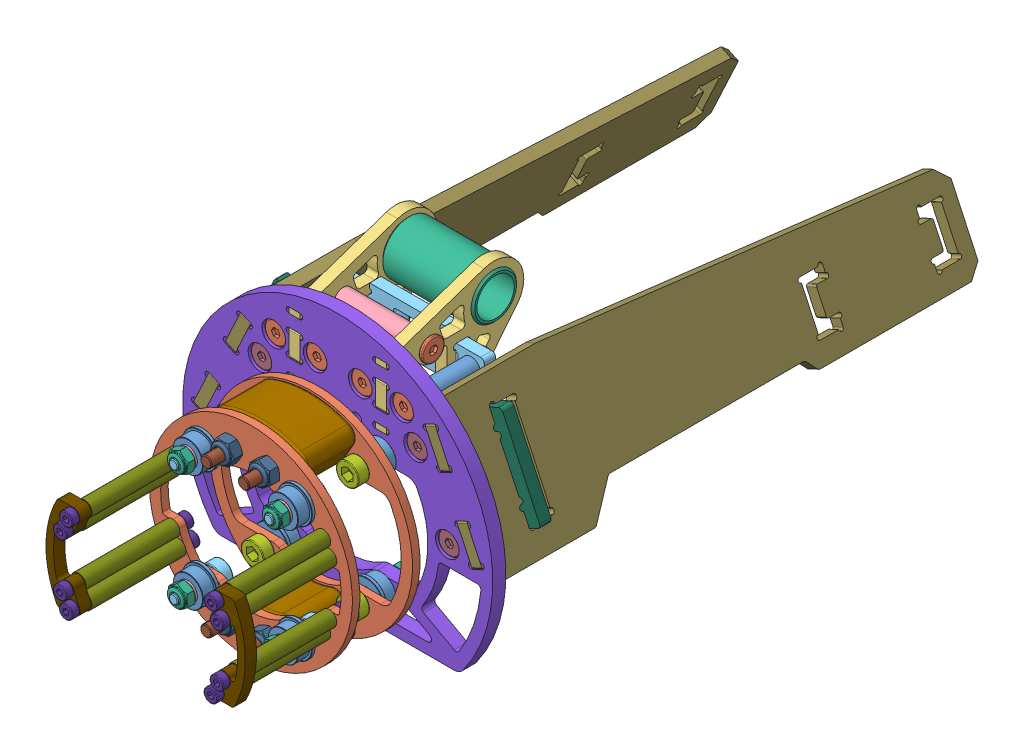
SolidWorks assembly 弹轮前轴系, configuration 默认. Lengths in mm.
Overall size (82.5 72.5 186.6).
121 component instances, 24 part files, 98 mates.
Components (placement in the parent):
- 法兰轴承3×8×4-1: 法兰轴承3×8×4 [默认] at (-12.6392 15.5 11.1) x (-0.660582 -0.750754 0) z (0 0 1) size (9.2 9.2 4)
- 弹轮前轴承板1_2mm-1: 弹轮前轴承板1_2mm [弹轮前轴承板1（限位）_2mm] at (0 0 8) size (54 54 2)
- 3×5×0.1 平垫-1: 3×5×0.1 平垫 [默认] at (-12.6392 15.5 9.05) size (5 5 0.1)
- 3×5×0.5 平垫-1: 3×5×0.5 平垫 [默认] at (-12.6392 15.5 13.35) size (5 5 0.5)
- 3×5×0.5 平垫-2: 3×5×0.5 平垫 [默认] at (12.6392 15.5 13.35) x (-1 0 0) z (0 0 -1) size (5 5 0.5)
- 法兰轴承3×8×4-2: 法兰轴承3×8×4 [默认] at (12.6392 15.5 11.1) x (-0.660582 0.750754 0) z (0 0 1) size (9.2 9.2 4)
- 3×5×0.1 平垫-2: 3×5×0.1 平垫 [默认] at (12.6392 15.5 9.05) x (-1 0 0) z (0 0 -1) size (5 5 0.1)
- 3×6×M2.5塞打螺丝-1: 3×6×M2.5塞打螺丝 [默认] at (-12.6392 15.5 10.5) x (0 0 1) z (-0.999028 0.044087 0) size (13 6 6)
- 3×6×M2.5塞打螺丝-2: 3×6×M2.5塞打螺丝 [默认] at (12.6392 15.5 10.5) x (0 0 1) z (-0.999028 -0.044087 0) size (13 6 6)
- M2.5防松-1: M2.5防松 [默认] at (-12.6392 15.5 14.75) x (-0.917308 -0.398178 0) z (-0.398178 0.917308 0) size (5.77 2.99 5)
- M2.5防松-2: M2.5防松 [默认] at (12.6392 15.5 14.75) x (0.917308 -0.398178 0) z (-0.398178 -0.917308 0) size (5.77 2.99 5)
- 3×5×0.5 平垫-3: 3×5×0.5 平垫 [默认] at (-12.6392 -15.5 13.35) x (1 0 0) z (0 0 -1) size (5 5 0.5)
- 法兰轴承3×8×4-3: 法兰轴承3×8×4 [默认] at (-12.6392 -15.5 11.1) x (0.660582 -0.750754 0) z (0 0 1) size (9.2 9.2 4)
- 3×5×0.1 平垫-3: 3×5×0.1 平垫 [默认] at (-12.6392 -15.5 9.05) x (1 0 0) z (0 0 -1) size (5 5 0.1)
- 3×6×M2.5塞打螺丝-3: 3×6×M2.5塞打螺丝 [默认] at (-12.6392 -15.5 10.5) x (0 0 1) z (0.999028 0.044087 0) size (13 6 6)
- M2.5防松-3: M2.5防松 [默认] at (-12.6392 -15.5 14.75) x (-0.917308 0.398178 0) z (0.398178 0.917308 0) size (5.77 2.99 5)
- 3×5×0.5 平垫-4: 3×5×0.5 平垫 [默认] at (12.6392 -15.5 13.35) x (-1 0 0) z (0 0 1) size (5 5 0.5)
- 法兰轴承3×8×4-4: 法兰轴承3×8×4 [默认] at (12.6392 -15.5 11.1) x (0.660582 0.750754 0) z (0 0 1) size (9.2 9.2 4)
- 3×5×0.1 平垫-4: 3×5×0.1 平垫 [默认] at (12.6392 -15.5 9.05) x (-1 0 0) z (0 0 1) size (5 5 0.1)
- 3×6×M2.5塞打螺丝-4: 3×6×M2.5塞打螺丝 [默认] at (12.6392 -15.5 10.5) x (0 0 1) z (0.999028 -0.044087 0) size (13 6 6)
- M2.5防松-4: M2.5防松 [默认] at (12.6392 -15.5 14.75) x (0.917308 0.398178 0) z (0.398178 -0.917308 0) size (5.77 2.99 5)
- 弹轮前轴承板1_2mm-3: 弹轮前轴承板1_2mm [默认] at (0 0 -8) size (54 54 2)
- 3×5×0.1 平垫-5: 3×5×0.1 平垫 [默认] at (12.6392 -15.5 -9.05) x (-1 0 0) z (0 0 1) size (5 5 0.1)
- 法兰轴承3×8×4-5: 法兰轴承3×8×4 [默认] at (12.6392 -15.5 -11.1) x (-0.660582 -0.750754 0) z (0 0 -1) size (9.2 9.2 4)
- 3×5×0.1 平垫-6: 3×5×0.1 平垫 [默认] at (-12.6392 -15.5 -9.05) x (1 0 0) z (0 0 -1) size (5 5 0.1)
- 法兰轴承3×8×4-6: 法兰轴承3×8×4 [默认] at (-12.6392 -15.5 -11.1) x (-0.660582 0.750754 0) z (0 0 -1) size (9.2 9.2 4)
- 3×5×0.1 平垫-7: 3×5×0.1 平垫 [默认] at (-12.6392 15.5 -9.05) size (5 5 0.1)
- 法兰轴承3×8×4-7: 法兰轴承3×8×4 [默认] at (-12.6392 15.5 -11.1) x (0.660582 0.750754 0) z (0 0 -1) size (9.2 9.2 4)
- 3×5×0.1 平垫-8: 3×5×0.1 平垫 [默认] at (12.6392 15.5 -9.05) x (-1 0 0) z (0 0 -1) size (5 5 0.1)
- 法兰轴承3×8×4-8: 法兰轴承3×8×4 [默认] at (12.6392 15.5 -11.1) x (0.660582 -0.750754 0) z (0 0 -1) size (9.2 9.2 4)
- 3×10×M2.5塞打螺丝-1: 3×10×M2.5塞打螺丝 [默认] at (-12.6392 -15.5 -12.5) x (0 0 -1) z (0.867305 -0.497776 0) size (17 6 6)
- 3×10×M2.5塞打螺丝-2: 3×10×M2.5塞打螺丝 [默认] at (12.6392 -15.5 -12.5) x (0 0 -1) z (0.867305 0.497776 0) size (17 6 6)
- 3×10×M2.5塞打螺丝-3: 3×10×M2.5塞打螺丝 [默认] at (-12.6392 15.5 -12.5) x (0 0 -1) z (-0.867305 -0.497776 0) size (17 6 6)
- 3×10×M2.5塞打螺丝-4: 3×10×M2.5塞打螺丝 [默认] at (12.6392 15.5 -12.5) x (0 0 -1) z (-0.867305 0.497776 0) size (17 6 6)
- 3×5×0.5 平垫-5: 3×5×0.5 平垫 [默认] at (-12.6392 15.5 -13.35) size (5 5 0.5)
- 3×5×0.5 平垫-6: 3×5×0.5 平垫 [默认] at (12.6392 15.5 -13.35) x (-1 0 0) z (0 0 -1) size (5 5 0.5)
- 3×5×0.5 平垫-7: 3×5×0.5 平垫 [默认] at (-12.6392 -15.5 -13.35) x (1 0 0) z (0 0 -1) size (5 5 0.5)
- 3×5×0.5 平垫-8: 3×5×0.5 平垫 [默认] at (12.6392 -15.5 -13.35) x (-1 0 0) z (0 0 1) size (5 5 0.5)
- 弹轮前轴承板2_3.5mm-1: 弹轮前轴承板2_3.5mm [默认] at (0 0 -15.85) x (-1 0 0) z (0 0 1) size (82.5 66.75 3.5)
- M2.5防松-5: M2.5防松 [默认] at (-12.6392 15.5 -18.75) x (1 0 0) z (0 1 0) size (5.77 2.99 5)
- M2.5防松-6: M2.5防松 [默认] at (12.6392 15.5 -18.75) x (-1 0 0) z (0 -1 0) size (5.77 2.99 5)
- M2.5防松-7: M2.5防松 [默认] at (-12.6392 -15.5 -18.75) x (1 0 0) z (0 1 0) size (5.77 2.99 5)
- M2.5防松-8: M2.5防松 [默认] at (12.6392 -15.5 -18.75) x (-1 0 0) z (0 -1 0) size (5.77 2.99 5)
- 3×5×0.5 平垫-9: 3×5×0.5 平垫 [默认] at (-12.6392 15.5 -13.85) size (5 5 0.5)
- 3×5×0.5 平垫-10: 3×5×0.5 平垫 [默认] at (12.6392 15.5 -13.85) x (-1 0 0) z (0 0 -1) size (5 5 0.5)
- 3×5×0.5 平垫-11: 3×5×0.5 平垫 [默认] at (-12.6392 -15.5 -13.85) x (1 0 0) z (0 0 -1) size (5 5 0.5)
- 3×5×0.5 平垫-12: 3×5×0.5 平垫 [默认] at (12.6392 -15.5 -13.85) x (-1 0 0) z (0 0 1) size (5 5 0.5)
- 弹轮前轴系垫块-1: 弹轮前轴系垫块 [默认] at origin size (24.62 12.25 14.46)
- 弹轮前轴系垫块-2: 弹轮前轴系垫块 [默认] x (1 0 0) z (0 0 -1) size (24.62 12.25 14.46)
- M3防松-1: M3防松 [默认] at (-5 -19.5 10.4) x (1 0 0) z (0 -1 0) size (6.24 3.5 5.4)
- M3防松-2: M3防松 [默认] at (5 -19.5 10.4) x (-0.923728 -0.383049 0) z (-0.383049 0.923728 0) size (6.24 3.5 5.4)
- M3防松-3: M3防松 [默认] at (5 19.5 10.4) x (-0.923728 0.383049 0) z (0.383049 0.923728 0) size (6.24 3.5 5.4)
- M3防松-4: M3防松 [默认] at (-5 19.5 10.4) x (1 0 0) z (0 -1 0) size (6.24 3.5 5.4)
- M3×25扁头螺丝-1: M3×25扁头螺丝 [默认] at (5 -19.5 -9.5) x (-0.697349 0.716732 0) z (0 0 -1) size (6 6 26)
- M3×25扁头螺丝-2: M3×25扁头螺丝 [默认] at (-5 -19.5 -9.5) x (-0.570437 0.821341 0) z (0 0 -1) size (6 6 26)
- M3×25扁头螺丝-3: M3×25扁头螺丝 [默认] at (5 19.5 -9.5) x (0.697349 0.716732 0) z (0 0 -1) size (6 6 26)
- M3×25扁头螺丝-4: M3×25扁头螺丝 [默认] at (-5 19.5 -9.5) x (0.570437 0.821341 0) z (0 0 -1) size (6 6 26)
- 弹轮-轨道连接板1_3mm-1: 弹轮-轨道连接板1_3mm [默认] at (-30.8145 14.369 -82.6) x (0 0 1) z (-0.906308 0.422618 0) size (133.5 38 3)
- M3×6扁头螺丝-1: M3×6扁头螺丝 [默认] at (-20.6973 20.6851 -15.1) size (6 6 7)
- M3×6扁头螺丝-2: M3×6扁头螺丝 [默认] at (-29.1496 2.5589 -15.1) x (0.985984 -0.166838 0) z (0 0 1) size (6 6 7)
- M3×Φ5×10-1: M3×Φ5×10 [默认] at (-29.1496 2.5589 -22.6) size (5 5 10)
- M3×Φ5×10-2: M3×Φ5×10 [默认] at (-20.6973 20.6851 -22.6) size (5 5 10)
- 弹轮前轴承板3_3mm-1: 弹轮前轴承板3_3mm [默认] at (-24.9235 11.622 -29.1) x (0.906308 -0.422618 0) z (0 0 1) size (14.97 27 3)
- M3×6扁头螺丝-3: M3×6扁头螺丝 [默认] at (-20.6973 20.6851 -31.1) x (0.679475 0.733699 0) z (0 0 -1) size (6 6 7)
- M3×6扁头螺丝-4: M3×6扁头螺丝 [默认] at (-29.1496 2.5589 -31.1) x (0.733685 0.67949 0) z (0 0 -1) size (6 6 7)
- M3×6扁头螺丝-5: M3×6扁头螺丝 [默认] at (29.1496 2.5589 -31.1) x (0.733685 -0.67949 0) z (0 0 -1) size (6 6 7)
- M3×Φ5×10-3: M3×Φ5×10 [默认] at (29.1496 2.5589 -22.6) x (-1 0 0) z (0 0 -1) size (5 5 10)
- 弹轮前轴承板3_3mm-2: 弹轮前轴承板3_3mm [默认] at (24.9235 11.622 -29.1) x (-0.906308 -0.422618 0) z (0 0 -1) size (14.97 27 3)
- M3×Φ5×10-4: M3×Φ5×10 [默认] at (20.6973 20.6851 -22.6) x (-1 0 0) z (0 0 -1) size (5 5 10)
- M3×6扁头螺丝-6: M3×6扁头螺丝 [默认] at (20.6973 20.6851 -31.1) x (0.679475 -0.733699 0) z (0 0 -1) size (6 6 7)
- 弹轮-轨道连接板1_3mm-2: 弹轮-轨道连接板1_3mm [默认] at (30.8145 14.369 -82.6) x (0 0 1) z (-0.906308 -0.422618 0) size (133.5 38 3)
- M3×6扁头螺丝-7: M3×6扁头螺丝 [默认] at (29.1496 2.5589 -15.1) x (0.985984 0.166838 0) z (0 0 1) size (6 6 7)
- M3×6扁头螺丝-8: M3×6扁头螺丝 [默认] at (20.6973 20.6851 -15.1) size (6 6 7)
- M2×Φ4×25铝柱-1: M2×Φ4×25铝柱 [默认] at (-20.8567 -7 21.5) x (-0.830926 -0.556383 0) z (0 0 1) size (4 4 25)
- M2×Φ4×25铝柱-2: M2×Φ4×25铝柱 [默认] at (-19.2445 -10.6607 21.5) x (0.982865 0.184326 0) z (0 0 1) size (4 4 25)
- M2×8圆柱头螺丝-1: M2×8圆柱头螺丝 [默认] at (-19.2445 -10.6607 10) x (0 0 1) z (-0.980095 -0.198528 0) size (10 3.6 3.6)
- M2×8圆柱头螺丝-2: M2×8圆柱头螺丝 [默认] at (-20.8567 -7 10) x (0 0 1) z (-1 0 0) size (10 3.6 3.6)
- M2×8圆柱头螺丝-3: M2×8圆柱头螺丝 [默认] at (-19.2445 -10.6607 34) x (0 0 -1) z (0.941359 0.337405 0) size (10 3.6 3.6)
- M2×8圆柱头螺丝-4: M2×8圆柱头螺丝 [默认] at (-20.8567 -7 34) x (0 0 -1) z (0.953351 0.301864 0) size (10 3.6 3.6)
- M2×Φ4×25铝柱-3: M2×Φ4×25铝柱 [默认] at (20.8567 -7 21.5) x (0.830926 -0.556383 0) z (0 0 -1) size (4 4 25)
- M2×Φ4×25铝柱-4: M2×Φ4×25铝柱 [默认] at (19.2445 -10.6607 21.5) x (-0.982865 0.184326 0) z (0 0 -1) size (4 4 25)
- M2×8圆柱头螺丝-5: M2×8圆柱头螺丝 [默认] at (19.2445 -10.6607 34) x (0 0 -1) z (0.941359 -0.337405 0) size (10 3.6 3.6)
- M2×8圆柱头螺丝-6: M2×8圆柱头螺丝 [默认] at (20.8567 -7 34) x (0 0 -1) z (0.953351 -0.301864 0) size (10 3.6 3.6)
- M2×8圆柱头螺丝-7: M2×8圆柱头螺丝 [默认] at (19.2445 -10.6607 10) x (0 0 1) z (-0.980095 0.198528 0) size (10 3.6 3.6)
- M2×8圆柱头螺丝-8: M2×8圆柱头螺丝 [默认] at (20.8567 -7 10) x (0 0 1) z (-1 0 0) size (10 3.6 3.6)
- M2×8圆柱头螺丝-9: M2×8圆柱头螺丝 [默认] at (-20.8567 7 34) x (0 0 -1) z (-0.953351 0.301864 0) size (10 3.6 3.6)
- M2×8圆柱头螺丝-10: M2×8圆柱头螺丝 [默认] at (-19.2445 10.6607 34) x (0 0 -1) z (-0.941359 0.337405 0) size (10 3.6 3.6)
- M2×Φ4×25铝柱-5: M2×Φ4×25铝柱 [默认] at (-20.8567 7 21.5) x (-0.830926 0.556383 0) z (0 0 -1) size (4 4 25)
- M2×Φ4×25铝柱-6: M2×Φ4×25铝柱 [默认] at (-19.2445 10.6607 21.5) x (0.982865 -0.184326 0) z (0 0 -1) size (4 4 25)
- M2×8圆柱头螺丝-11: M2×8圆柱头螺丝 [默认] at (-19.2445 10.6607 10) x (0 0 1) z (0.980095 -0.198528 0) size (10 3.6 3.6)
- M2×8圆柱头螺丝-12: M2×8圆柱头螺丝 [默认] at (-20.8567 7 10) x (0 0 1) z (1 0 0) size (10 3.6 3.6)
- M2×8圆柱头螺丝-13: M2×8圆柱头螺丝 [默认] at (19.2445 10.6607 34) x (0 0 -1) z (-0.941359 -0.337405 0) size (10 3.6 3.6)
- M2×8圆柱头螺丝-14: M2×8圆柱头螺丝 [默认] at (20.8567 7 34) x (0 0 -1) z (-0.953351 -0.301864 0) size (10 3.6 3.6)
- M2×Φ4×25铝柱-7: M2×Φ4×25铝柱 [默认] at (19.2445 10.6607 21.5) x (-0.982865 -0.184326 0) z (0 0 1) size (4 4 25)
- M2×Φ4×25铝柱-8: M2×Φ4×25铝柱 [默认] at (20.8567 7 21.5) x (0.830926 0.556383 0) z (0 0 1) size (4 4 25)
- M2×8圆柱头螺丝-15: M2×8圆柱头螺丝 [默认] at (19.2445 10.6607 10) x (0 0 1) z (0.980095 0.198528 0) size (10 3.6 3.6)
- M2×8圆柱头螺丝-16: M2×8圆柱头螺丝 [默认] at (20.8567 7 10) x (0 0 1) z (1 0 0) size (10 3.6 3.6)
- 弹轮前轴承板1附属限位片_3mm-5: 弹轮前轴承板1附属限位片_3mm [默认] at (0 0 35.5) size (9.06 24.92 3)
- 弹轮前轴承板1附属限位片_3mm-6: 弹轮前轴承板1附属限位片_3mm [默认] at (0 0 35.5) x (-1 0 0) z (0 0 -1) size (9.06 24.92 3)
- M3×Φ5×15-1: M3×Φ5×15 [默认] at (-17 28 -25.1) x (0.736847 -0.67606 0) z (0 0 1) size (5 5 15)
- M3×Φ5×15-2: M3×Φ5×15 [默认] at (-6 28 -25.1) x (0.98447 -0.175554 0) z (0 0 1) size (5 5 15)
- M3×8扁头螺丝-1: M3×8扁头螺丝 [默认] at (-6 28 -15.1) size (6 6 9)
- M3×8扁头螺丝-2: M3×8扁头螺丝 [默认] at (-17 28 -15.1) size (6 6 9)
- 底座连接板_3mm-1: 底座连接板_3mm [默认] at (-11.5 37.5 -42.6) x (0 0 -1) z (-1 0 0) size (36.5 27 3)
- M3×Φ5×20-1: M3×Φ5×20 [默认] at (0 34 -25.6) x (0 0.22486 0.974391) z (-1 0 0) size (5 5 20)
- M3×Φ5×20-2: M3×Φ5×20 [默认] at (0 22 -25.6) x (0 0.999587 -0.028752) z (1 0 0) size (5 5 20)
- M3×8扁头螺丝-3: M3×8扁头螺丝 [默认] at (-13.5 22 -25.6) x (0 0 1) z (-1 0 0) size (6 6 9)
- M3×8扁头螺丝-4: M3×8扁头螺丝 [默认] at (-13.5 34 -25.6) x (0 -0.007898 0.999969) z (-1 0 0) size (6 6 9)
- 底座连接板辅助固定板_3mm-1: 底座连接板辅助固定板_3mm [默认] at (-0.0001 28.0273 -34.1) x (0.99999 0.004545 0) z (0 0 1) size (41 12 3)
- M3×8扁头螺丝-5: M3×8扁头螺丝 [默认] at (-6 28 -36.1) x (-0.661002 0.750384 0) z (0 0 -1) size (6 6 9)
- M3×8扁头螺丝-6: M3×8扁头螺丝 [默认] at (-16.9999 27.95 -36.1) x (-0.990764 -0.135598 0) z (0 0 -1) size (6 6 9)
- M3×8扁头螺丝-7: M3×8扁头螺丝 [默认] at (6 28 -36.1) x (-0.661002 -0.750384 0) z (0 0 -1) size (6 6 9)
- M3×8扁头螺丝-8: M3×8扁头螺丝 [默认] at (16.9999 27.95 -36.1) x (-0.990764 0.135598 0) z (0 0 -1) size (6 6 9)
- 底座连接板_3mm-2: 底座连接板_3mm [默认] at (11.5 37.5 -42.6) x (0 0 -1) z (-1 0 0) size (36.5 27 3)
- M3×Φ5×15-3: M3×Φ5×15 [默认] at (17 28 -25.1) x (-0.736847 -0.67606 0) z (0 0 -1) size (5 5 15)
- M3×Φ5×15-4: M3×Φ5×15 [默认] at (6 28 -25.1) x (-0.98447 -0.175554 0) z (0 0 -1) size (5 5 15)
- M3×8扁头螺丝-9: M3×8扁头螺丝 [默认] at (13.5 22 -25.6) x (0 0 -1) z (1 0 0) size (6 6 9)
- M3×8扁头螺丝-10: M3×8扁头螺丝 [默认] at (13.5 34 -25.6) x (0 0.007898 -0.999969) z (1 0 0) size (6 6 9)
- M3×8扁头螺丝-11: M3×8扁头螺丝 [默认] at (17 28 -15.1) size (6 6 9)
- M3×8扁头螺丝-12: M3×8扁头螺丝 [默认] at (6 28 -15.1) size (6 6 9)
- 底座连接轴套-1: 底座连接轴套 [默认] at (0 37.5 -42.6) size (27 14 14)
Mates (geometry in assembly coordinates):
- 重合1: coincident aligned: plane of 弹轮前轴承板1_2mm-1 through (0 0 8) normal (1 0 0)
- 重合2: coincident aligned: plane of 弹轮前轴承板1_2mm-1 through (0 0 8) normal (0 1 0)
- 同心1: concentric aligned: cylinder of 法兰轴承3×8×4-1 through (-12.6392 15.5 13.1) axis (0 0 -1) radius 1.5; cylinder of 3×5×0.1 平垫-1 through (-12.6392 15.5 9.1) axis (0 0 -1) radius 1.5
- 同心2: concentric aligned: cylinder of 法兰轴承3×8×4-1 through (-12.6392 15.5 13.1) axis (0 0 -1) radius 1.5; cylinder of 3×5×0.5 平垫-1 through (-12.6392 15.5 13.6) axis (0 0 -1) radius 1.5
- 重合4: coincident anti-aligned: plane of 法兰轴承3×8×4-1 through (-12.6392 15.5 13.1) normal (0 0 1); plane of 3×5×0.5 平垫-1 through (-12.6392 15.5 13.1) normal (0 0 -1)
- 重合5: coincident anti-aligned: plane of 法兰轴承3×8×4-1 through (-12.6392 15.5 9.1) normal (0 0 -1); plane of 3×5×0.1 平垫-1 through (-12.6392 15.5 9.1) normal (0 0 1)
- 同心3: concentric aligned: cylinder of 法兰轴承3×8×4-1 through (-12.6392 15.5 13.1) axis (0 0 -1) radius 1.5; cylinder of 弹轮前轴承板1_2mm-1 through (-12.6392 15.5 9) axis (0 0 -1) radius 1.5
- 重合6: coincident anti-aligned: plane of 弹轮前轴承板1_2mm-1 through (0 0 9) normal (0 0 1); plane of 3×5×0.1 平垫-1 through (-12.6392 15.5 9) normal (0 0 -1)
- 同心4: concentric aligned: cylinder of 法兰轴承3×8×4-1 through (-12.6392 15.5 13.1) axis (0 0 -1) radius 1.5; cylinder of 3×6×M2.5塞打螺丝-1 through (-12.6392 15.5 4) axis (0 0 -1) radius 1.5
- 重合7: coincident anti-aligned: plane of 弹轮前轴承板1_2mm-1 through (0 0 7) normal (0 0 -1); plane of 3×6×M2.5塞打螺丝-1 through (-12.507 18.4971 7) normal (0 0 1)
- 同心6: concentric aligned: cylinder of 3×6×M2.5塞打螺丝-1 through (-12.6392 15.5 4) axis (0 0 -1) radius 1.25; cylinder of M2.5防松-1 through (-12.6392 15.5 15.9) axis (0 0 -1) radius 1.25
- 重合8: coincident anti-aligned: plane of 3×5×0.5 平垫-1 through (-12.6392 15.5 13.6) normal (0 0 1); plane of M2.5防松-1 through (-12.6392 15.5 13.6) normal (0 0 -1)
- 同心7: concentric anti-aligned: cylinder of 弹轮前轴承板1_2mm-3 through (-12.6392 -15.5 -7) axis (0 0 -1) radius 1.5; cylinder of 3×10×M2.5塞打螺丝-1 through (-12.6392 -15.5 -4) axis (0 0 1) radius 1.5
- 重合9: coincident anti-aligned: plane of 弹轮前轴承板1_2mm-3 through (0 0 -7) normal (0 0 1); plane of 3×10×M2.5塞打螺丝-1 through (-11.1459 -12.8981 -7) normal (0 0 -1)
- 重合11: coincident anti-aligned: plane of 弹轮前轴承板2_3.5mm-1 through (0 0 -17.6) normal (0 0 -1); plane of M2.5防松-5 through (-12.6392 15.5 -17.6) normal (0 0 1)
- 同心11: concentric aligned: cylinder of 3×10×M2.5塞打螺丝-3 through (-12.6392 15.5 -4) axis (0 0 1) radius 1.25; cylinder of M2.5防松-5 through (-12.6392 15.5 -19.9) axis (0 0 1) radius 1.25
- 同心12: concentric anti-aligned: cylinder of 3×10×M2.5塞打螺丝-4 through (12.6392 15.5 -4) axis (0 0 1) radius 1.5; cylinder of 弹轮前轴承板2_3.5mm-1 through (12.6392 15.5 -14.1) axis (0 0 -1) radius 1.5
- 同心13: concentric anti-aligned: cylinder of 3×10×M2.5塞打螺丝-3 through (-12.6392 15.5 -4) axis (0 0 1) radius 1.5; cylinder of 弹轮前轴承板2_3.5mm-1 through (-12.6392 15.5 -14.1) axis (0 0 -1) radius 1.5
- 重合12: coincident anti-aligned: plane of 3×5×0.5 平垫-5 through (-12.6392 15.5 -13.6) normal (0 0 -1); plane of 3×5×0.5 平垫-9 through (-12.6392 15.5 -13.6) normal (0 0 1)
- 同心15: concentric anti-aligned: cylinder of 3×10×M2.5塞打螺丝-3 through (-12.6392 15.5 -4) axis (0 0 1) radius 1.5; cylinder of 3×5×0.5 平垫-9 through (-12.6392 15.5 -13.6) axis (0 0 -1) radius 1.5
- 重合13: coincident anti-aligned: plane of 弹轮前轴承板2_3.5mm-1 through (0 0 -14.1) normal (0 0 1); plane of 3×5×0.5 平垫-9 through (-12.6392 15.5 -14.1) normal (0 0 -1)
- 同心16: concentric aligned: cylinder of 弹轮前轴承板1_2mm-1 through (-5 -19.5 7) axis (0 0 1) radius 1.55; cylinder of 弹轮前轴系垫块-2 through (-5 -19.5 -7) axis (0 0 1) radius 1.55
- 同心17: concentric aligned: cylinder of 弹轮前轴承板1_2mm-1 through (5 -19.5 7) axis (0 0 1) radius 1.55; cylinder of 弹轮前轴系垫块-2 through (5 -19.5 -7) axis (0 0 1) radius 1.55
- 重合14: coincident anti-aligned: plane of 弹轮前轴承板1_2mm-1 through (0 0 7) normal (0 0 -1); plane of 弹轮前轴系垫块-2 through (0 0 7) normal (0 0 1)
- 同心18: concentric anti-aligned: cylinder of 弹轮前轴承板1_2mm-1 through (-5 19.5 7) axis (0 0 1) radius 1.55; cylinder of 弹轮前轴系垫块-1 through (-5 19.5 7) axis (0 0 -1) radius 1.55
- 同心19: concentric anti-aligned: cylinder of 弹轮前轴承板1_2mm-1 through (5 19.5 7) axis (0 0 1) radius 1.55; cylinder of 弹轮前轴系垫块-1 through (5 19.5 7) axis (0 0 -1) radius 1.55
- 重合15: coincident anti-aligned: plane of 弹轮前轴承板1_2mm-1 through (0 0 7) normal (0 0 -1); plane of 弹轮前轴系垫块-1 through (0 0 7) normal (0 0 1)
- 重合16: coincident anti-aligned: plane of 弹轮前轴承板1_2mm-3 through (0 0 -7) normal (0 0 1); plane of 弹轮前轴系垫块-2 through (0 0 -7) normal (0 0 -1)
- 重合17: coincident anti-aligned: plane of 弹轮前轴承板1_2mm-1 through (0 0 9) normal (0 0 1); plane of M3防松-1 through (-5 -19.5 9) normal (0 0 -1)
- 同心20: concentric aligned: cylinder of 弹轮前轴承板1_2mm-1 through (-5 -19.5 7) axis (0 0 1) radius 1.55; cylinder of M3防松-1 through (-5 -19.5 9) axis (0 0 1) radius 1.5
- 同心21: concentric aligned: cylinder of 弹轮前轴承板1_2mm-1 through (5 -19.5 7) axis (0 0 1) radius 1.55; cylinder of M3防松-2 through (5 -19.5 9) axis (0 0 1) radius 1.5
- 重合18: coincident anti-aligned: plane of 弹轮前轴承板1_2mm-1 through (0 0 9) normal (0 0 1); plane of M3防松-2 through (5 -19.5 9) normal (0 0 -1)
- 重合19: coincident anti-aligned: plane of 弹轮前轴承板1_2mm-3 through (0 0 -9) normal (0 0 -1); plane of M3×25扁头螺丝-2 through (-5 -19.5 -9) normal (0 0 1)
- 同心22: concentric anti-aligned: cylinder of 弹轮前轴承板1_2mm-3 through (-5 -19.5 -9) axis (0 0 1) radius 1.55; cylinder of M3×25扁头螺丝-2 through (-5 -19.5 16) axis (0 0 -1) radius 1.5
- 同心23: concentric anti-aligned: cylinder of 弹轮前轴承板1_2mm-3 through (5 -19.5 -9) axis (0 0 1) radius 1.55; cylinder of M3×25扁头螺丝-1 through (5 -19.5 16) axis (0 0 -1) radius 1.5
- 重合20: coincident anti-aligned: plane of 弹轮前轴承板1_2mm-3 through (0 0 -9) normal (0 0 -1); plane of M3×25扁头螺丝-1 through (5 -19.5 -9) normal (0 0 1)
- 重合21: coincident anti-aligned: plane of 弹轮前轴承板2_3.5mm-1 through (0 0 -17.6) normal (0 0 -1); plane of 弹轮-轨道连接板1_3mm-1 through (-40.2037 -2.2169 -17.6) normal (0 0 1)
- 对称1: symmetric aligned: plane of 弹轮前轴承板2_3.5mm-1 through (-34.2644 10.4608 -14.1) normal (0.906308 -0.422618 0); plane of 弹轮-轨道连接板1_3mm-1 through (-31.5908 9.2141 -14.1) normal (-0.906308 0.422618 0); plane of 弹轮前轴承板2_3.5mm-1 through (-30.8145 14.369 -82.6) normal (-0.906308 0.422618 0)
- 宽度1: width anti-aligned: plane of 弹轮前轴承板2_3.5mm-1 through (-31.5908 9.2141 -14.1) normal (-0.422618 -0.906308 0); plane of 弹轮-轨道连接板1_3mm-1 through (-27.3646 18.2772 -14.1) normal (0.422618 0.906308 0); plane of 弹轮前轴承板2_3.5mm-1 through (-31.5681 9.2036 -14.1) normal (0.422618 0.906308 0); plane of 弹轮-轨道连接板1_3mm-1 through (-27.3419 18.2666 -14.1) normal (-0.422618 -0.906308 0)
- 同心24: concentric anti-aligned: cylinder of 弹轮前轴承板2_3.5mm-1 through (-29.1496 2.5589 -14.1) axis (0 0 -1) radius 1.55; cylinder of M3×6扁头螺丝-2 through (-29.1496 2.5589 -21.6) axis (0 0 1) radius 1.5
- 重合22: coincident anti-aligned: plane of 弹轮前轴承板2_3.5mm-1 through (-29.1496 2.5589 -15.6) normal (0 0 1); plane of M3×6扁头螺丝-2 through (-29.1496 2.5589 -15.6) normal (0 0 -1)
- 同心25: concentric anti-aligned: cylinder of 弹轮前轴承板2_3.5mm-1 through (-20.6973 20.6851 -14.1) axis (0 0 -1) radius 1.55; cylinder of M3×6扁头螺丝-1 through (-20.6973 20.6851 -21.6) axis (0 0 1) radius 1.5
- 重合23: coincident anti-aligned: plane of 弹轮前轴承板2_3.5mm-1 through (-20.6973 20.6851 -15.6) normal (0 0 1); plane of M3×6扁头螺丝-1 through (-20.6973 20.6851 -15.6) normal (0 0 -1)
- 重合24: coincident anti-aligned: plane of 弹轮前轴承板2_3.5mm-1 through (0 0 -17.6) normal (0 0 -1); plane of M3×Φ5×10-1 through (-29.1496 2.5589 -17.6) normal (0 0 1)
- 重合25: coincident anti-aligned: plane of 弹轮前轴承板2_3.5mm-1 through (0 0 -17.6) normal (0 0 -1); plane of M3×Φ5×10-2 through (-20.6973 20.6851 -17.6) normal (0 0 1)
- 同心26: concentric anti-aligned: cylinder of M3×6扁头螺丝-1 through (-20.6973 20.6851 -21.6) axis (0 0 1) radius 1.5; cylinder of M3×Φ5×10-2 through (-20.6973 20.6851 -17.6) axis (0 0 -1) radius 1.5
- 同心27: concentric anti-aligned: cylinder of M3×6扁头螺丝-2 through (-29.1496 2.5589 -21.6) axis (0 0 1) radius 1.5; cylinder of M3×Φ5×10-1 through (-29.1496 2.5589 -17.6) axis (0 0 -1) radius 1.5
- 同心28: concentric aligned: cylinder of M3×Φ5×10-1 through (-29.1496 2.5589 -17.6) axis (0 0 -1) radius 1.5; cylinder of 弹轮前轴承板3_3mm-1 through (-29.1496 2.5589 -27.6) axis (0 0 -1) radius 1.55
- 同心29: concentric aligned: cylinder of M3×Φ5×10-2 through (-20.6973 20.6851 -17.6) axis (0 0 -1) radius 1.5; cylinder of 弹轮前轴承板3_3mm-1 through (-20.6973 20.6851 -27.6) axis (0 0 -1) radius 1.55
- 重合26: coincident anti-aligned: plane of M3×Φ5×10-1 through (-29.1496 2.5589 -27.6) normal (0 0 -1); plane of 弹轮前轴承板3_3mm-1 through (-29.1496 2.5589 -27.6) normal (0 0 1)
- 同心30: concentric aligned: cylinder of 弹轮前轴承板3_3mm-1 through (-29.1496 2.5589 -27.6) axis (0 0 -1) radius 1.55; cylinder of M3×6扁头螺丝-4 through (-29.1496 2.5589 -24.6) axis (0 0 -1) radius 1.5
- 同心31: concentric aligned: cylinder of 弹轮前轴承板3_3mm-1 through (-20.6973 20.6851 -27.6) axis (0 0 -1) radius 1.55; cylinder of M3×6扁头螺丝-3 through (-20.6973 20.6851 -24.6) axis (0 0 -1) radius 1.5
- 重合27: coincident anti-aligned: plane of 弹轮前轴承板3_3mm-1 through (-29.1496 2.5589 -30.6) normal (0 0 -1); plane of M3×6扁头螺丝-3 through (-20.6973 20.6851 -30.6) normal (0 0 1)
- 重合28: coincident anti-aligned: plane of 弹轮前轴承板3_3mm-1 through (-29.1496 2.5589 -30.6) normal (0 0 -1); plane of M3×6扁头螺丝-4 through (-29.1496 2.5589 -30.6) normal (0 0 1)
- 同心32: concentric aligned: cylinder of 弹轮前轴承板1_2mm-1 through (-19.2445 -10.6607 9) axis (0 0 -1) radius 1; cylinder of M2×Φ4×25铝柱-2 through (-19.2445 -10.6607 34) axis (0 0 -1) radius 1
- 同心33: concentric aligned: cylinder of 弹轮前轴承板1_2mm-1 through (-20.8567 -7 9) axis (0 0 -1) radius 1; cylinder of M2×Φ4×25铝柱-1 through (-20.8567 -7 34) axis (0 0 -1) radius 1
- 重合29: coincident anti-aligned: plane of 弹轮前轴承板1_2mm-1 through (0 0 9) normal (0 0 1); plane of M2×Φ4×25铝柱-2 through (-19.2445 -10.6607 9) normal (0 0 -1)
- 重合30: coincident anti-aligned: plane of 弹轮前轴承板1_2mm-1 through (0 0 9) normal (0 0 1); plane of M2×Φ4×25铝柱-1 through (-20.8567 -7 9) normal (0 0 -1)
- 同心34: concentric anti-aligned: cylinder of 弹轮前轴承板1_2mm-1 through (-19.2445 -10.6607 9) axis (0 0 -1) radius 1; cylinder of M2×8圆柱头螺丝-1 through (-19.2445 -10.6607 15) axis (0 0 1) radius 1
- 重合31: coincident anti-aligned: plane of 弹轮前轴承板1_2mm-1 through (0 0 7) normal (0 0 -1); plane of M2×8圆柱头螺丝-1 through (-19.6018 -8.8965 7) normal (0 0 1)
- 重合32: coincident anti-aligned: plane of 弹轮前轴承板1_2mm-1 through (0 0 7) normal (0 0 -1); plane of M2×8圆柱头螺丝-2 through (-20.8567 -5.2 7) normal (0 0 1)
- 同心35: concentric anti-aligned: cylinder of 弹轮前轴承板1_2mm-1 through (-20.8567 -7 9) axis (0 0 -1) radius 1; cylinder of M2×8圆柱头螺丝-2 through (-20.8567 -7 15) axis (0 0 1) radius 1
- 同心40: concentric aligned: cylinder of M2×Φ4×25铝柱-2 through (-19.2445 -10.6607 34) axis (0 0 -1) radius 1; cylinder of M2×8圆柱头螺丝-3 through (-19.2445 -10.6607 29) axis (0 0 -1) radius 1
- 同心41: concentric aligned: cylinder of M2×Φ4×25铝柱-1 through (-20.8567 -7 34) axis (0 0 -1) radius 1; cylinder of M2×8圆柱头螺丝-4 through (-20.8567 -7 29) axis (0 0 -1) radius 1
- 同心42: concentric aligned: cylinder of M2×8圆柱头螺丝-3 through (-19.2445 -10.6607 29) axis (0 0 -1) radius 1; cylinder of 弹轮前轴承板1附属限位片_3mm-5 through (-19.2445 -10.6607 37) axis (0 0 -1) radius 1
- 同心44: concentric aligned: cylinder of M2×8圆柱头螺丝-4 through (-20.8567 -7 29) axis (0 0 -1) radius 1; cylinder of 弹轮前轴承板1附属限位片_3mm-5 through (-20.8567 -7 37) axis (0 0 -1) radius 1
- 重合36: coincident anti-aligned: plane of M2×Φ4×25铝柱-2 through (-19.2445 -10.6607 34) normal (0 0 1); plane of 弹轮前轴承板1附属限位片_3mm-5 through (-9.6222 5.3304 34) normal (0 0 -1)
- 重合37: coincident anti-aligned: plane of M2×8圆柱头螺丝-3 through (-19.8518 -8.9663 37) normal (0 0 -1); plane of 弹轮前轴承板1附属限位片_3mm-5 through (-9.6222 5.3304 37) normal (0 0 1)
- 重合38: coincident anti-aligned: plane of M2×8圆柱头螺丝-4 through (-21.4 -5.284 37) normal (0 0 -1); plane of 弹轮前轴承板1附属限位片_3mm-5 through (-9.6222 5.3304 37) normal (0 0 1)
- 同心45: concentric aligned: cylinder of 弹轮前轴承板2_3.5mm-1 through (-17 28 -14.1) axis (0 0 -1) radius 1.55; cylinder of M3×Φ5×15-1 through (-17 28 -17.6) axis (0 0 -1) radius 1.5
- 同心46: concentric aligned: cylinder of 弹轮前轴承板2_3.5mm-1 through (-6 28 -14.1) axis (0 0 -1) radius 1.55; cylinder of M3×Φ5×15-2 through (-6 28 -17.6) axis (0 0 -1) radius 1.5
- 重合39: coincident anti-aligned: plane of 弹轮前轴承板2_3.5mm-1 through (0 0 -17.6) normal (0 0 -1); plane of M3×Φ5×15-1 through (-17 28 -17.6) normal (0 0 1)
- 重合40: coincident anti-aligned: plane of 弹轮前轴承板2_3.5mm-1 through (0 0 -17.6) normal (0 0 -1); plane of M3×Φ5×15-2 through (-6 28 -17.6) normal (0 0 1)
- 重合41: coincident anti-aligned: plane of 弹轮前轴承板2_3.5mm-1 through (20.6973 20.6851 -15.6) normal (0 0 1); plane of M3×8扁头螺丝-2 through (-17 28 -15.6) normal (0 0 -1)
- 同心47: concentric anti-aligned: cylinder of M3×Φ5×15-1 through (-17 28 -17.6) axis (0 0 -1) radius 1.5; cylinder of M3×8扁头螺丝-2 through (-17 28 -23.6) axis (0 0 1) radius 1.5
- 重合42: coincident anti-aligned: plane of 弹轮前轴承板2_3.5mm-1 through (20.6973 20.6851 -15.6) normal (0 0 1); plane of M3×8扁头螺丝-1 through (-6 28 -15.6) normal (0 0 -1)
- 同心48: concentric anti-aligned: cylinder of M3×Φ5×15-2 through (-6 28 -17.6) axis (0 0 -1) radius 1.5; cylinder of M3×8扁头螺丝-1 through (-6 28 -23.6) axis (0 0 1) radius 1.5
- 宽度2: width anti-aligned: plane of 底座连接板_3mm-1 through (-10 31.5 -17.6) normal (0 1 0); plane of 弹轮前轴承板2_3.5mm-1 through (-10 24.5 -17.6) normal (0 -1 0); plane of 底座连接板_3mm-1 through (-10.025 31.5 -14.1) normal (0 -1 0); plane of 弹轮前轴承板2_3.5mm-1 through (-10.025 24.5 -14.1) normal (0 1 0)
- 宽度3: width anti-aligned: plane of 底座连接板_3mm-1 through (-13 37.5 -42.6) normal (-1 0 0); plane of 弹轮前轴承板2_3.5mm-1 through (-10 37.5 -42.6) normal (1 0 0); plane of 底座连接板_3mm-1 through (-12.975 31.5 -14.1) normal (1 0 0); plane of 弹轮前轴承板2_3.5mm-1 through (-10.025 31.5 -14.1) normal (-1 0 0)
- 重合43: coincident anti-aligned: plane of 弹轮前轴承板2_3.5mm-1 through (0 0 -17.6) normal (0 0 -1); plane of 底座连接板_3mm-1 through (-13 18.5 -17.6) normal (0 0 1)
- 同心51: concentric anti-aligned: cylinder of 底座连接板_3mm-1 through (-13 22 -25.6) axis (1 0 0) radius 1.55; cylinder of M3×Φ5×20-2 through (10 22 -25.6) axis (-1 0 0) radius 1.5
- 重合44: coincident anti-aligned: plane of 底座连接板_3mm-1 through (-10 37.5 -42.6) normal (1 0 0); plane of M3×Φ5×20-2 through (-10 22 -25.6) normal (-1 0 0)
- 同心52: concentric aligned: cylinder of 底座连接板_3mm-1 through (-13 34 -25.6) axis (1 0 0) radius 1.55; cylinder of M3×Φ5×20-1 through (-10 34 -25.6) axis (1 0 0) radius 1.5
- 重合45: coincident anti-aligned: plane of 底座连接板_3mm-1 through (-10 37.5 -42.6) normal (1 0 0); plane of M3×Φ5×20-1 through (-10 34 -25.6) normal (-1 0 0)
- 重合46: coincident anti-aligned: plane of 底座连接板_3mm-1 through (-13 37.5 -42.6) normal (-1 0 0); plane of M3×8扁头螺丝-4 through (-13 34 -25.6) normal (1 0 0)
- 重合47: coincident anti-aligned: plane of 底座连接板_3mm-1 through (-13 37.5 -42.6) normal (-1 0 0); plane of M3×8扁头螺丝-3 through (-13 22 -25.6) normal (1 0 0)
- 同心53: concentric aligned: cylinder of M3×Φ5×20-2 through (10 22 -25.6) axis (-1 0 0) radius 1.5; cylinder of M3×8扁头螺丝-3 through (-5 22 -25.6) axis (-1 0 0) radius 1.5
- 同心54: concentric anti-aligned: cylinder of M3×Φ5×20-1 through (-10 34 -25.6) axis (1 0 0) radius 1.5; cylinder of M3×8扁头螺丝-4 through (-5 34 -25.6) axis (-1 0 0) radius 1.5
- 同心55: concentric aligned: cylinder of M3×Φ5×15-2 through (-6 28 -17.6) axis (0 0 -1) radius 1.5; cylinder of 底座连接板辅助固定板_3mm-1 through (-6 28 -32.6) axis (0 0 -1) radius 1.55
- 相切1: tangent aligned: cylinder of M3×Φ5×15-1 through (-17 28 -17.6) axis (0 0 -1) radius 1.5; cylinder of 底座连接板辅助固定板_3mm-1 through (-16.9999 27.95 -32.6) axis (0 0 -1) radius 1.55
- 重合48: coincident anti-aligned: plane of M3×Φ5×15-2 through (-6 28 -32.6) normal (0 0 -1); plane of 底座连接板辅助固定板_3mm-1 through (-0.0001 28.0273 -32.6) normal (0 0 1)
- 同心56: concentric aligned: cylinder of 底座连接板辅助固定板_3mm-1 through (-16.9999 27.95 -32.6) axis (0 0 -1) radius 1.55; cylinder of M3×8扁头螺丝-6 through (-16.9999 27.95 -27.6) axis (0 0 -1) radius 1.5
- 重合49: coincident anti-aligned: plane of 底座连接板辅助固定板_3mm-1 through (-0.0001 28.0273 -35.6) normal (0 0 -1); plane of M3×8扁头螺丝-5 through (-6 28 -35.6) normal (0 0 1)
- 重合50: coincident anti-aligned: plane of 底座连接板辅助固定板_3mm-1 through (-0.0001 28.0273 -35.6) normal (0 0 -1); plane of M3×8扁头螺丝-6 through (-16.9999 27.95 -35.6) normal (0 0 1)
- 同心57: concentric aligned: cylinder of M3×Φ5×15-2 through (-6 28 -17.6) axis (0 0 -1) radius 1.5; cylinder of M3×8扁头螺丝-5 through (-6 28 -27.6) axis (0 0 -1) radius 1.5
- 重合51: coincident aligned: plane of 底座连接轴套-1 through (0 37.5 -42.6) normal (1 0 0)
- 同心58: concentric aligned: cylinder of 底座连接板_3mm-2 through (10 37.5 -42.6) axis (1 0 0) radius 6; cylinder of 底座连接轴套-1 through (13.5 37.5 -42.6) axis (1 0 0) radius 6.025
- 平行1: parallel aligned: plane of 底座连接轴套-1 through (0 37.5 -42.6) normal (0 1 0)
